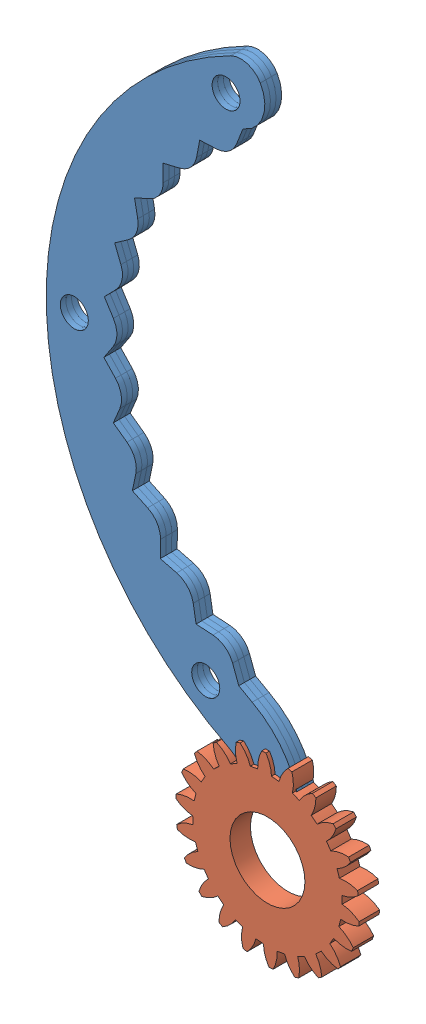
SolidWorks assembly Assem1, configuration Default. Lengths in mm.
Overall size (29.51 69.7 1.82).
4 component instances, 2 part files, 10 mates.
Components (placement in the parent):
- kiskac1-sol-1: kiskac1-sol [Varsayılan] at (56.4151 88.2085 85.4856) size (25 65.23 0.5)
- gear-1: gear [Default] at (26.7546 49.2233 88.1446) x (0 0 -1) z (0.983606 0.180329 0) size (1.82 16.25 16.36)
- kiskac1-sol-2: kiskac1-sol [Varsayılan] at (56.4151 88.2085 85.9856) size (25 65.23 0.5)
- kiskac1-sol-3: kiskac1-sol [Varsayılan] at (56.4151 88.2085 86.4856) size (25 65.23 0.5)
Mates (geometry in assembly coordinates):
- Coincident1: coincident aligned: plane of kiskac1-sol-1 through (21.8206 103.4244 85.7356) normal (0 0 -1); plane of gear-1 through (20.4808 38.0723 85.7356) normal (0 0 -1)
- Concentric2: concentric anti-aligned: circle of kiskac1-sol-1; circle of gear-1
- Coincident2: coincident anti-aligned: plane of kiskac1-sol-1 through (21.8206 103.4244 86.2356) normal (0 0 1); plane of kiskac1-sol-2 through (21.8206 103.4244 86.2356) normal (0 0 -1)
- Concentric3: concentric aligned: circle of kiskac1-sol-1; circle of kiskac1-sol-2
- Concentric4: concentric aligned: circle of kiskac1-sol-1; circle of kiskac1-sol-2
- Concentric5: concentric aligned: circle of kiskac1-sol-1; circle of kiskac1-sol-2
- Coincident5: coincident anti-aligned: plane of kiskac1-sol-2 through (21.8206 103.4244 86.7356) normal (0 0 1); plane of kiskac1-sol-3 through (21.8206 103.4244 86.7356) normal (0 0 -1)
- Concentric6: concentric aligned: circle of kiskac1-sol-1; circle of kiskac1-sol-3
- Concentric7: concentric aligned: circle of kiskac1-sol-1; circle of kiskac1-sol-3
- Concentric8: concentric aligned: circle of kiskac1-sol-1; circle of kiskac1-sol-3
